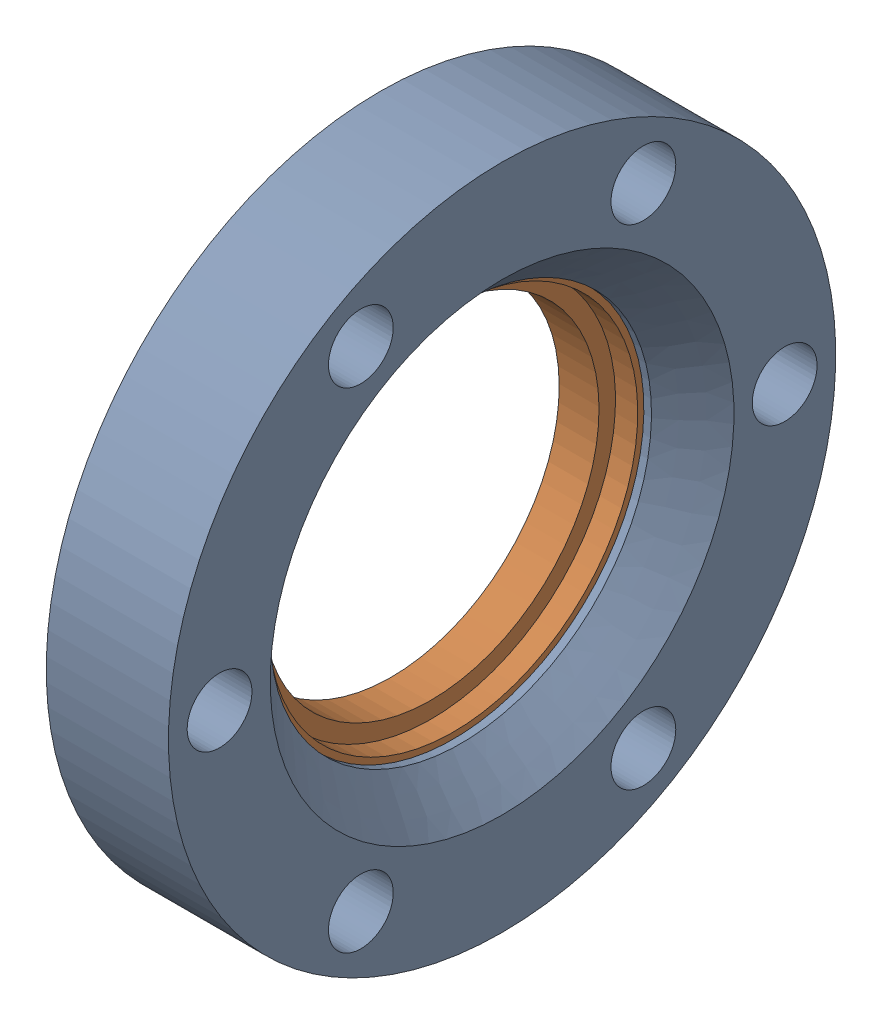
SolidWorks assembly 100014 (2.75 X 1.5 R)_pull, configuration Default. Lengths in mm.
Overall size (12.7 69.34 69.34).
2 component instances, 2 part files, 0 mates.
Components (placement in the parent):
- 100014 (2.75 X 1.5 REC)_pull-1: 100014 (2.75 X 1.5 REC)_pull [Default] at origin size (12.7 69.34 69.34)
- 100014 (2.75 X 1.5 INS)_pull-1: 100014 (2.75 X 1.5 INS)_pull [Default] at (1.17 0 0) x (1 0 0) z (0 0.994423 -0.105464) size (6.96 48.1 48.1)
